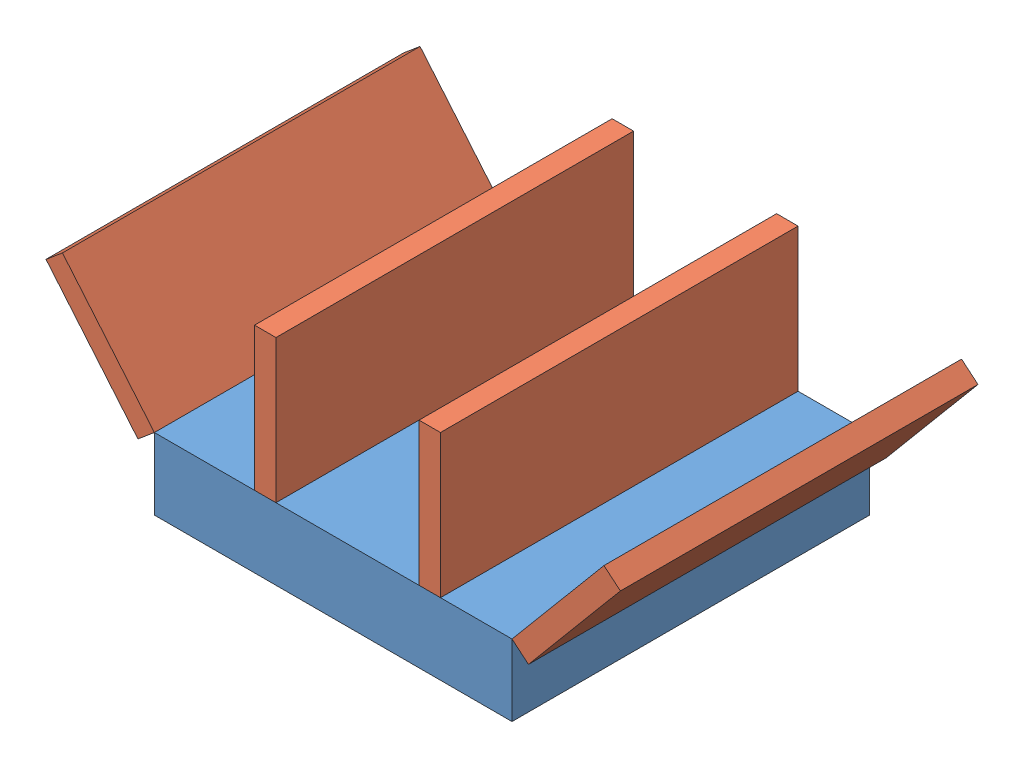
SolidWorks assembly Assembly 62 (Fix), configuration Default. Lengths in mm.
Overall size (203.98 76.2 127).
5 component instances, 2 part files, 14 mates.
Components (placement in the parent):
- Base_2013-1: Base_2013 [Default] at origin size (127 25.4 127)
- Wing_2013-1: Wing_2013 [Default] at (-27.94 76.2 63.5) x (0 -1 0) z (0 0 1) size (50.8 7.62 127)
- Wing_2013-2: Wing_2013 [Default] at (30.48 76.2 63.5) x (0 -1 0) z (0 0 1) size (50.8 7.62 127)
- Wing_2013-3: Wing_2013 [Default] at (-101.9909 59.417 63.5) x (0.642788 -0.766044 0) z (0 0 1) size (50.8 7.62 127)
- Wing_2013-4: Wing_2013 [Default] at (69.3373 20.502 63.5) x (0.642788 0.766044 0) z (0 0 1) size (50.8 7.62 127)
Mates (geometry in assembly coordinates):
- Coincident1: coordinate: point of Base_2013-1
- Coincident3: coincident: line of Base_2013-1 through (-63.5 25.4 -63.5) axis (0 0 1); line of Wing_2013-3 through (-63.5 25.4 63.5) axis (0 0 -1)
- Coincident4: coincident: plane of Base_2013-1 through (63.5 25.4 63.5) normal (0 0 1); plane of Wing_2013-3 through (-96.1536 64.3151 63.5) normal (0 0 1)
- Coincident5: coincident: plane of Base_2013-1 through (63.5 25.4 -63.5) normal (0 0 -1); plane of Wing_2013-3 through (-96.1536 64.3151 -63.5) normal (0 0 -1)
- Angle2: planar angle = 2.268928 rad anti-aligned: plane of Wing_2013-3 through (-96.1536 64.3151 63.5) normal (0.766044 0.642788 0); plane of Base_2013-1 through (0 25.4 0) normal (0 1 0)
- Coincident7: coincident: plane of Base_2013-1 through (0 25.4 0) normal (0 1 0); plane of Wing_2013-1 through (-20.32 25.4 63.5) normal (0 -1 0)
- Coincident8: coincident: plane of Base_2013-1 through (63.5 25.4 63.5) normal (0 0 1); plane of Wing_2013-1 through (-20.32 76.2 63.5) normal (0 0 1)
- Coincident9: coincident: plane of Base_2013-1 through (0 25.4 0) normal (0 1 0); plane of Wing_2013-2 through (38.1 25.4 63.5) normal (0 -1 0)
- Coincident10: coincident: plane of Base_2013-1 through (63.5 25.4 63.5) normal (0 0 1); plane of Wing_2013-2 through (38.1 76.2 63.5) normal (0 0 1)
- Distance1: distance = 25.4 mm: line of Wing_2013-2 through (38.1 76.2 63.5) axis (0 -1 0); line of Base_2013-1 through (63.5 25.4 63.5) axis (0 -1 0)
- Distance2: distance = 50.8 mm: line of Wing_2013-1 through (-20.32 76.2 63.5) axis (0 -1 0); line of Wing_2013-2 through (30.48 76.2 63.5) axis (0 -1 0)
- Coincident12: coincident: line of Base_2013-1 through (63.5 25.4 63.5) axis (0 0 -1); line of Wing_2013-4 through (63.5 25.4 -63.5) axis (0 0 1)
- Coincident13: coincident: plane of Base_2013-1 through (63.5 25.4 63.5) normal (0 0 1); plane of Wing_2013-4 through (63.5 25.4 63.5) normal (0 0 1)
- Angle3: planar angle = 2.268928 rad anti-aligned: plane of Base_2013-1 through (0 25.4 0) normal (0 1 0); plane of Wing_2013-4 through (63.5 25.4 63.5) normal (-0.766044 0.642788 0)
